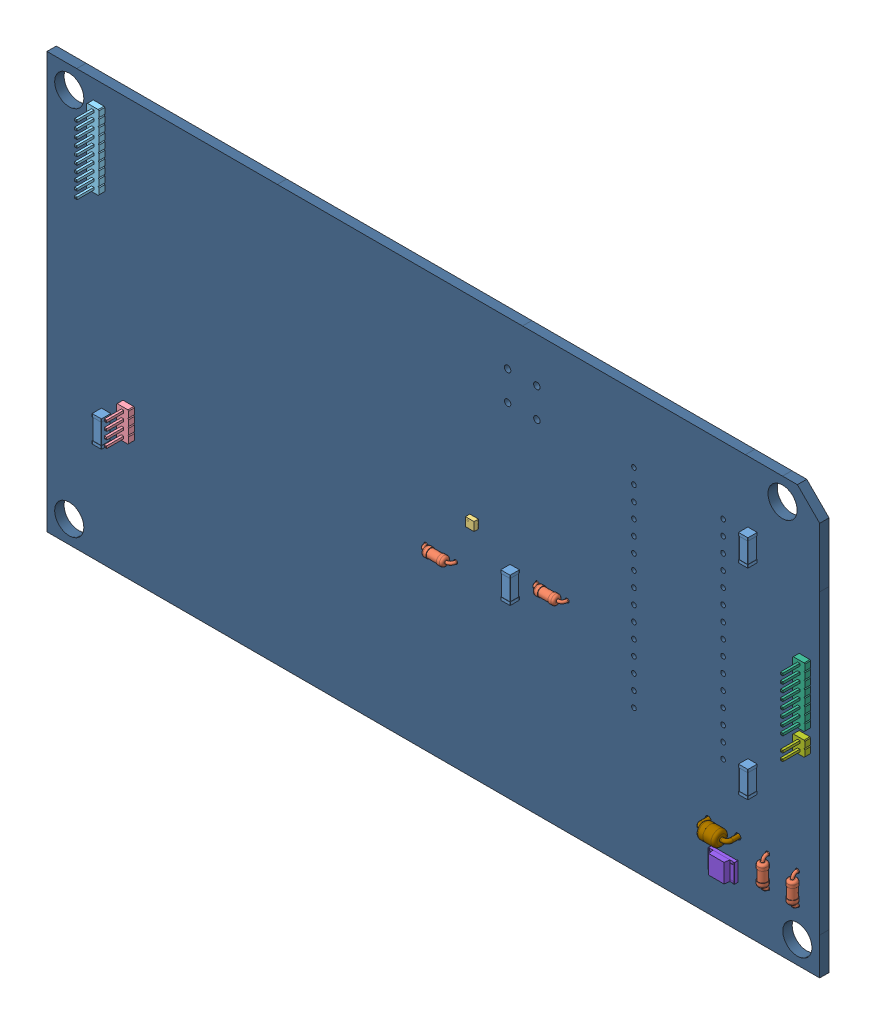
SolidWorks assembly water_quality, configuration Default. Lengths in mm.
Overall size (132.08 71.12 7).
32 component instances, 10 part files, 0 mates.
Components (placement in the parent):
- water_quality.step-1: water_quality.step [Default] at origin size (132.08 71.12 7)
  - C_1806_4516Metric.step-1: C_1806_4516Metric.step [Default] at (153.67 -74.93 1.65) x (0 1 0) z (0 0 1) size (4.5 1.6 1.6)
    - SOLID.step-1: SOLID.step [Default] at origin size (4.5 1.6 1.6)
  - C_1806_4516Metric.step-2: C_1806_4516Metric.step [Default] at (113.03 -100.7825 1.65) x (0 -1 0) z (0 0 1) size (4.5 1.6 1.6)
    - SOLID.step-1: SOLID.step [Default] at origin size (4.5 1.6 1.6)
  - C_1806_4516Metric.step-3: C_1806_4516Metric.step [Default] at (153.67 -109.22 1.65) x (0 -1 0) z (0 0 1) size (4.5 1.6 1.6)
    - SOLID.step-1: SOLID.step [Default] at origin size (4.5 1.6 1.6)
  - C_1806_4516Metric.step-4: C_1806_4516Metric.step [Default] at (43.18 -112.5775 1.65) x (0 -1 0) z (0 0 1) size (4.5 1.6 1.6)
    - SOLID.step-1: SOLID.step [Default] at origin size (4.5 1.6 1.6)
  - R_Axial_DIN0204_L3.6mm_D1.6mm_P5.08mm_Horizontal.step-1: R_Axial_DIN0204_L3.6mm_D1.6mm_P5.08mm_Horizontal.step [Default] at (102.87 -102.87 1.65) x (-1 0 0) z (0 0 1) size (5.58 1.6 4.6)
    - SOLID-0.step-1: SOLID-0.step [Default] at origin size (5.58 1.6 4.6)
  - R_Axial_DIN0204_L3.6mm_D1.6mm_P5.08mm_Horizontal.step-2: R_Axial_DIN0204_L3.6mm_D1.6mm_P5.08mm_Horizontal.step [Default] at (121.92 -99.06 1.65) x (-1 0 0) z (0 0 1) size (5.58 1.6 4.6)
    - SOLID-0.step-1: SOLID-0.step [Default] at origin size (5.58 1.6 4.6)
  - WSON-6_1.5x1.5mm_P0.5mm.step-1: WSON-6_1.5x1.5mm_P0.5mm.step [Default] at (106.105 -95.25 1.65) size (1.5 1.48 0.77)
    - SOLID-1.step-1: SOLID-1.step [Default] at origin size (1.5 1.48 0.77)
  - PinHeader_1x04_P1.27mm_Vertical.step-1: PinHeader_1x04_P1.27mm_Vertical.step [Default] at (46.99 -111.76 1.65) x (-1 0 0) z (0 0 1) size (2.1 5.08 6.3)
    - SOLID-2.step-1: SOLID-2.step [Default] at origin size (2.1 5.08 6.3)
  - PinHeader_1x10_P1.27mm_Vertical.step-1: PinHeader_1x10_P1.27mm_Vertical.step [Default] at (41.91 -66.04 1.65) size (2.1 12.7 6.3)
    - SOLID-3.step-1: SOLID-3.step [Default] at origin size (2.1 12.7 6.3)
  - PinHeader_1x08_P1.27mm_Vertical.step-1: PinHeader_1x08_P1.27mm_Vertical.step [Default] at (162.56 -96.52 1.65) x (-1 0 0) z (0 0 1) size (2.1 10.16 6.3)
    - SOLID-4.step-1: SOLID-4.step [Default] at origin size (2.1 10.16 6.3)
  - PinHeader_1x02_P1.27mm_Vertical.step-1: PinHeader_1x02_P1.27mm_Vertical.step [Default] at (162.56 -99.06 1.65) size (2.1 2.54 6.3)
    - SOLID-5.step-1: SOLID-5.step [Default] at origin size (2.1 2.54 6.3)
  - LED_1812_4532Metric.step-1: LED_1812_4532Metric.step [Default] at (148.9925 -124.46 1.65) size (4.5 3.2 1.5)
    - SOLID-6.step-1: SOLID-6.step [Default] at origin size (4.5 3.2 1.5)
  - D_T-1_P5.08mm_Horizontal.step-1: D_T-1_P5.08mm_Horizontal.step [Default] at (146.05 -119.38 1.65) size (5.78 2.62 5.61)
    - SOLID-7.step-1: SOLID-7.step [Default] at origin size (5.78 2.62 5.61)
  - R_Axial_DIN0204_L3.6mm_D1.6mm_P5.08mm_Horizontal.step-3: R_Axial_DIN0204_L3.6mm_D1.6mm_P5.08mm_Horizontal.step [Default] at (161.29 -124.46 1.65) x (0 1 0) z (0 0 1) size (5.58 1.6 4.6)
    - SOLID-0.step-1: SOLID-0.step [Default] at origin size (5.58 1.6 4.6)
  - R_Axial_DIN0204_L3.6mm_D1.6mm_P5.08mm_Horizontal.step-4: R_Axial_DIN0204_L3.6mm_D1.6mm_P5.08mm_Horizontal.step [Default] at (156.21 -119.38 1.65) x (0 -1 0) z (0 0 1) size (5.58 1.6 4.6)
    - SOLID-0.step-1: SOLID-0.step [Default] at origin size (5.58 1.6 4.6)
  - COMPOUND.step-1: COMPOUND.step [Default] at origin size (132.08 71.12 1.6)
